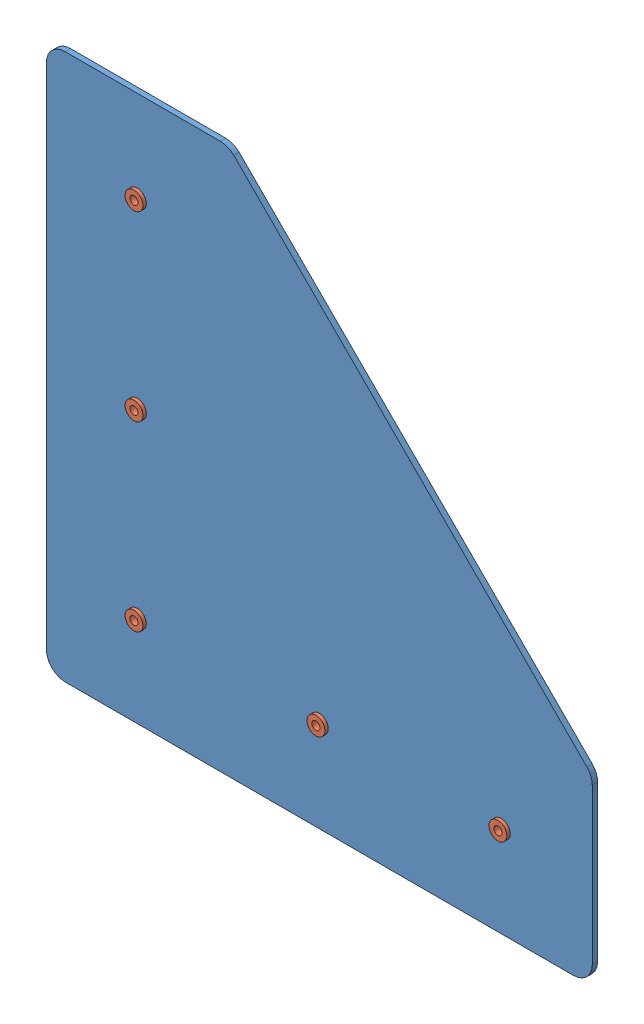
SolidWorks assembly corner_w_rivets170927, configuration Default. Lengths in mm.
Overall size (161.93 161.93 7).
6 component instances, 2 part files, 10 mates.
Components (placement in the parent):
- 2inch_90degCorner170927-1: 2inch_90degCorner170927 [Default] at (-1.9018 62.2183 172.3281) size (161.93 161.93 1.59)
- 0.3125 rivet170927-2: 0.3125 rivet170927 [Default] at (25.0857 197.1558 173.9156) x (1 0 0) z (0 -1 0) size (5.3 7 5.3)
- 0.3125 rivet170927-3: 0.3125 rivet170927 [Default] at (25.0857 143.1808 173.9156) x (0.987351 0.158553 0) z (0.158553 -0.987351 0) size (5.3 7 5.3)
- 0.3125 rivet170927-4: 0.3125 rivet170927 [Default] at (25.0857 89.2058 173.9156) x (0.959125 0.282984 0) z (0.282984 -0.959125 0) size (5.3 7 5.3)
- 0.3125 rivet170927-5: 0.3125 rivet170927 [Default] at (79.0607 89.2058 173.9156) x (0.928571 0.371154 0) z (0.371154 -0.928571 0) size (5.3 7 5.3)
- 0.3125 rivet170927-7: 0.3125 rivet170927 [Default] at (133.0357 89.2058 173.9156) x (0.906989 0.421154 0) z (0.421154 -0.906989 0) size (5.3 7 5.3)
Mates (geometry in assembly coordinates):
- Coincident1: coincident anti-aligned: plane of 2inch_90degCorner170927-1 through (-1.9018 62.2183 173.9156) normal (0 0 1); plane of 0.3125 rivet170927-2 through (23.4357 197.1558 173.9156) normal (0 0 -1)
- Concentric1: concentric anti-aligned: circle of 2inch_90degCorner170927-1; circle of 0.3125 rivet170927-2
- Coincident2: coincident anti-aligned: plane of 2inch_90degCorner170927-1 through (-1.9018 62.2183 173.9156) normal (0 0 1); plane of 0.3125 rivet170927-3 through (23.4566 142.9192 173.9156) normal (0 0 -1)
- Concentric2: concentric anti-aligned: circle of 2inch_90degCorner170927-1; circle of 0.3125 rivet170927-3
- Coincident3: coincident anti-aligned: plane of 2inch_90degCorner170927-1 through (-1.9018 62.2183 173.9156) normal (0 0 1); plane of 0.3125 rivet170927-4 through (23.5032 88.7389 173.9156) normal (0 0 -1)
- Concentric3: concentric anti-aligned: circle of 2inch_90degCorner170927-1; circle of 0.3125 rivet170927-4
- Coincident4: coincident anti-aligned: plane of 2inch_90degCorner170927-1 through (-1.9018 62.2183 173.9156) normal (0 0 1); plane of 0.3125 rivet170927-5 through (77.5286 88.5934 173.9156) normal (0 0 -1)
- Concentric4: concentric anti-aligned: circle of 2inch_90degCorner170927-1; circle of 0.3125 rivet170927-5
- Coincident6: coincident anti-aligned: plane of 2inch_90degCorner170927-1 through (-1.9018 62.2183 173.9156) normal (0 0 1); plane of 0.3125 rivet170927-7 through (131.5392 88.5109 173.9156) normal (0 0 -1)
- Concentric6: concentric aligned: circle of 2inch_90degCorner170927-1; circle of 0.3125 rivet170927-7
